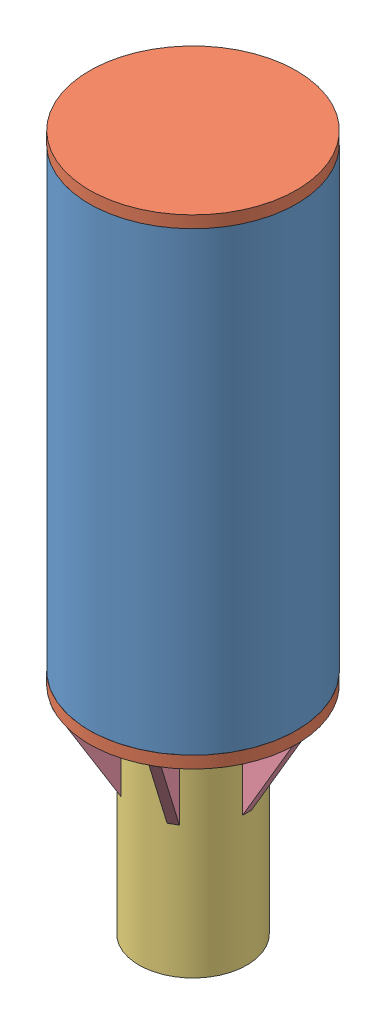
SolidWorks assembly base_pin, configuration Default. Lengths in mm.
Overall size (219.07 736.6 219.07).
10 component instances, 4 part files, 12 mates.
Components (placement in the parent):
- tube^base_pin-1: tube^base_pin [Default] at origin size (219.07 482.6 219.07) (virtual)
- plate^base_pin-1: plate^base_pin [Default] at (0 -254 0) size (219.07 12.7 219.07) (virtual)
- plate^base_pin-2: plate^base_pin [Default] at (0 241.3 0) size (219.07 12.7 219.07) (virtual)
- pin^base_pin-1: pin^base_pin [Default] at (0 -368.3 0) size (114.3 228.6 114.3) (virtual)
- gusset^base_pin-1: gusset^base_pin [Default] at (0 -241.3 0) x (-1 0 0) z (0 0 -1) size (52.39 88.9 9.53) (virtual)
- gusset^base_pin-2: gusset^base_pin [Default] at (0 -241.3 0) x (-0.5 0 -0.866025) z (0.866025 0 -0.5) size (52.39 88.9 9.53) (virtual)
- gusset^base_pin-3: gusset^base_pin [Default] at (0 -241.3 0) x (0.5 0 -0.866025) z (0.866025 0 0.5) size (52.39 88.9 9.53) (virtual)
- gusset^base_pin-4: gusset^base_pin [Default] at (0 -241.3 0) size (52.39 88.9 9.53) (virtual)
- gusset^base_pin-5: gusset^base_pin [Default] at (0 -241.3 0) x (0.5 0 0.866025) z (-0.866025 0 0.5) size (52.39 88.9 9.53) (virtual)
- gusset^base_pin-6: gusset^base_pin [Default] at (0 -241.3 0) x (-0.5 0 0.866025) z (-0.866025 0 -0.5) size (52.39 88.9 9.53) (virtual)
Mates (geometry in assembly coordinates):
- Concentric1: concentric aligned: cylinder of tube^base_pin-1 through (0 241.3 0) axis (0 -1 0) radius 109.5375; cylinder of plate^base_pin-2 through (0 254 0) axis (0 -1 0) radius 109.5375
- Coincident1: coincident anti-aligned: plane of tube^base_pin-1 through (0 241.3 0) normal (0 1 0); plane of plate^base_pin-2 through (0 241.3 0) normal (0 -1 0)
- Coincident2: coincident anti-aligned: plane of tube^base_pin-1 through (0 -241.3 0) normal (0 -1 0); plane of plate^base_pin-1 through (0 -241.3 0) normal (0 1 0)
- Coincident3: coincident anti-aligned: cylinder of tube^base_pin-1 through (0 241.3 0) axis (0 -1 0) radius 109.5375; circle of plate^base_pin-1
- Concentric2: concentric aligned: cylinder of tube^base_pin-1 through (0 241.3 0) axis (0 -1 0) radius 109.5375; cylinder of pin^base_pin-1 through (0 -254 0) axis (0 -1 0) radius 57.15
- Coincident4: coincident anti-aligned: plane of plate^base_pin-1 through (0 -254 0) normal (0 -1 0); plane of pin^base_pin-1 through (0 -254 0) normal (0 1 0)
- Coincident8: coincident anti-aligned: plane of tube^base_pin-1 through (0 0 0) normal (0 0 1); plane of gusset^base_pin-1 through (0 -241.3 0) normal (0 0 -1)
- Tangent1: tangent anti-aligned: plane of gusset^base_pin-1 through (57.15 -254 -4.7625) normal (-1 0 0); cylinder of pin^base_pin-1 through (0 -254 0) axis (0 -1 0) radius 57.15
- Coincident9: coincident anti-aligned: plane of plate^base_pin-1 through (0 -254 0) normal (0 -1 0); plane of gusset^base_pin-1 through (109.5375 -254 -4.7625) normal (0 1 0)
- Coincident10: coincident aligned: plane of plate^base_pin-1 through (0 -254 0) normal (1 0 0); plane of assembly
- Coincident11: coincident aligned: plane of plate^base_pin-2 through (0 241.3 0) normal (1 0 0); plane of assembly
- Coincident12: coincident aligned: plane of pin^base_pin-1 through (0 -368.3 0) normal (1 0 0)
